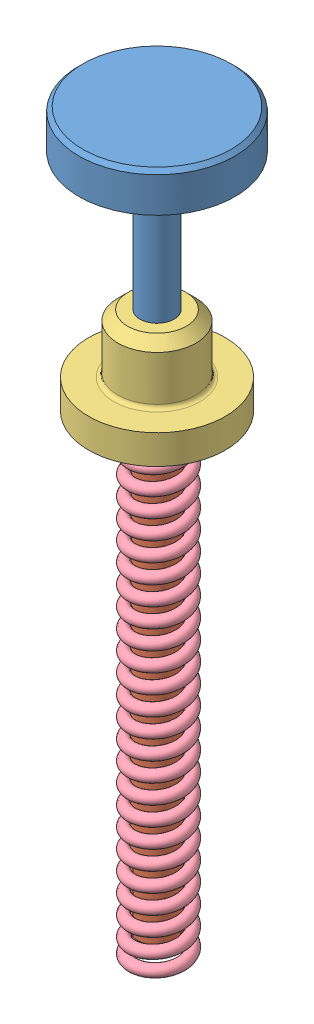
SolidWorks assembly Plunger, configuration Default. Lengths in mm.
Overall size (8 38.09 8).
4 component instances, 4 part files, 4 mates.
Components (placement in the parent):
- Plunger Button-1: Plunger Button [Default] at (-0.0641 3.1147 10.6111) size (8 11 8)
- Plunger Spring Shaft-1: Plunger Spring Shaft [Default] at (-0.0641 2.6147 10.6111) x (1 0 0) z (0 -1 0) size (2 2 25)
- Plunger Spring-Button Mate-1: Plunger Spring-Button Mate [Default] at (-0.0641 0.6147 10.6111) size (7 4.5 7)
- 9657K294_Compression Spring-1: 9657K294_Compression Spring [9657K294] at (0.2039 1.1759 10.8003) x (0.000076 0.008726 -0.999962) z (0.008726 0.999924 0.008727) size (3.64 3.64 25.4)
Mates (geometry in assembly coordinates):
- Concentric1: concentric aligned: cylinder of Plunger Button-1 through (-0.0641 14.1147 10.6111) axis (0 1 0) radius 0.875; cylinder of Plunger Spring-Button Mate-1 through (-0.0641 3.1147 10.6111) axis (0 1 0) radius 0.875
- Coincident1: coincident anti-aligned: plane of Plunger Button-1 through (-0.0641 3.1147 10.6111) normal (0 -1 0); plane of Plunger Spring-Button Mate-1 through (-0.0641 3.1147 10.6111) normal (0 1 0)
- Concentric2: concentric anti-aligned: cylinder of Plunger Spring Shaft-1 through (-0.0641 -22.3853 10.6111) axis (0 1 0) radius 1; cylinder of Plunger Spring-Button Mate-1 through (-0.0641 2.6147 10.6111) axis (0 -1 0) radius 1.2
- Coincident2: coincident anti-aligned: plane of Plunger Spring Shaft-1 through (-0.0641 2.6147 10.6111) normal (0 1 0); plane of Plunger Spring-Button Mate-1 through (1.1359 2.6147 10.6111) normal (0 -1 0)
